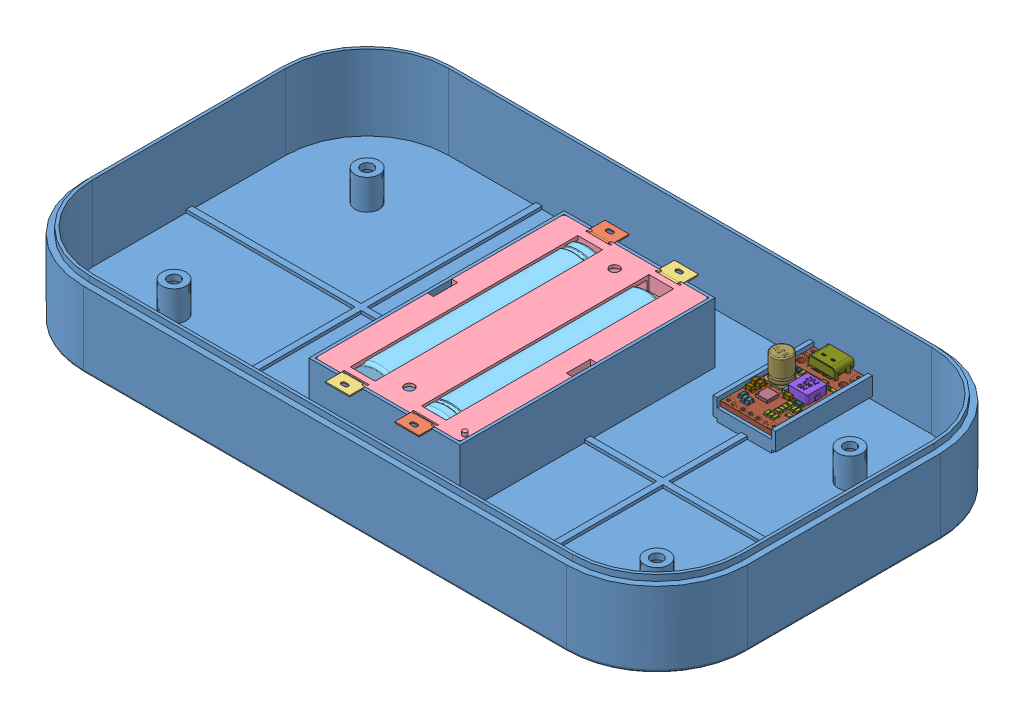
SolidWorks assembly Assem4, configuration Default. Lengths in mm.
Overall size (220 29 124).
46 component instances, 17 part files, 6 mates.
Components (placement in the parent):
- Part Bawah-1: Part Bawah [Default] at (99.8411 94.4112 166.5811) size (220 29 124)
- Hold_21700-2p_smd_bat-1: Hold_21700-2p_smd_bat [Default] at (99.8411 116.4112 166.5811) x (1 0 0) z (0 -1 0) size (48 92.64 22.3)
  - Hold_21700_Con_smd_p-1: Hold_21700_Con_smd_p [Default] at (-11.5 -40 0.8) size (8 9.53 15.7)
  - Hold_21700_Con_smd_m-1: Hold_21700_Con_smd_m [Default] at (-11.5 40 0.8) x (-1 0 0) z (0 0 1) size (8 12.94 15.7)
  - Hold_21700-2p_smd_1-1: Hold_21700-2p_smd_1 [Default] at origin size (48 82.5 17.3)
  - 21700-1: 21700 [Default] at (11.5 36.5 10.5) x (0 0 -1) z (0 1 0) size (21 21 70.2)
  - Hold_21700_Con_smd_p-2: Hold_21700_Con_smd_p [Default] at (11.5 40 0.8) x (-1 0 0) z (0 0 1) size (8 9.53 15.7)
  - Hold_21700_Con_smd_m-2: Hold_21700_Con_smd_m [Default] at (11.5 -40 0.8) size (8 12.94 15.7)
  - 21700-2: 21700 [Default] at (-11.5 -36.5 10.5) x (1 0 0) z (0 -1 0) size (21 21 70.2)
- Penutup baterai-3: Penutup baterai [Default] at (99.8411 95.4112 166.5811) x (1 0 0) z (0 0 -1) size (54 3 94)
- CHARGER BOARD 2S 15W-1: CHARGER BOARD 2S 15W [Default] at (150.6641 102.3529 127.6118) x (0 0 -1) z (1 0 0) size (32.1 10.03 18)
  - 0603-1: 0603 [Default] at (-1.1693 0.1284 6.1184) x (1 0 0) z (0 -1 0) size (2.4 1 0.47)
  - APH0630T-1: APH0630T [Default] at (2.0307 -0.2416 -0.5316) x (0 0 1) z (-1 0 0) size (7 2.9 6.6)
  - Ceramic_Capacitor_0805-1: Ceramic_Capacitor_0805 [Default] at (0.9557 -0.3416 0.8684) x (0 0 1) z (0 1 0) size (3.2 1.65 1.31)
  - LED-1: LED [Default] at (10.5807 -0.3416 -6.4316) x (1 0 0) z (0 1 0) size (1.6 0.8 0.6)
  - LED-2: LED [Default] at (10.5807 -0.3416 -5.1316) x (1 0 0) z (0 1 0) size (1.6 0.8 0.6)
  - PCB BD-1: PCB BD [Default] at (-10.9693 -0.3416 7.9684) size (31 1.64 18)
  - 100uF 35V001-1: 100uF 35V001 [Default] at (5.1507 -0.3416 -5.5516) x (1 0 0) z (0 1 0) size (8.58 8.74 8.41)
  - QFN-16 (4x4x0.9).step-1: QFN-16 (4x4x0.9).step [Default] at (-2.0393 -0.3416 -3.1116) x (1 0 0) z (0 1 0) size (4 4 0.92)
  - Ceramic_Capacitor_0805-2: Ceramic_Capacitor_0805 [Default] at (-2.6443 -0.3416 -8.2316) x (0 0 1) z (0 1 0) size (3.2 1.65 1.31)
  - Ceramic_Capacitor_0805-3: Ceramic_Capacitor_0805 [Default] at (0.0307 -0.3416 -7.3566) x (1 0 0) z (0 1 0) size (3.2 1.65 1.31)
  - Ceramic_Capacitor_0805-4: Ceramic_Capacitor_0805 [Default] at (0.0307 -0.3416 -9.0566) x (1 0 0) z (0 1 0) size (3.2 1.65 1.31)
  - Ceramic_Capacitor_0805-5: Ceramic_Capacitor_0805 [Default] at (10.5557 -0.3416 3.1684) x (0 0 1) z (0 1 0) size (3.2 1.65 1.31)
  - Ceramic_Capacitor_0603-1: Ceramic_Capacitor_0603 [Default] at (2.5307 -0.4668 -1.4816) x (1 0 0) z (0 1 0) size (2.56 1.32 1.05)
  - Ceramic_Capacitor_0603-2: Ceramic_Capacitor_0603 [Default] at (-6.6693 -0.4668 -5.8516) x (1 0 0) z (0 1 0) size (2.56 1.32 1.05)
  - Ceramic_Capacitor_0603-3: Ceramic_Capacitor_0603 [Default] at (-6.6693 -0.4668 -4.4316) x (1 0 0) z (0 1 0) size (2.56 1.32 1.05)
  - 0805-1: 0805 [Default] at (-5.5693 0.1827 -7.5816) x (1 0 0) z (0 -1 0) size (3.04 1.32 0.58)
  - 0805-2: 0805 [Default] at (0.9557 0.1827 4.2684) x (0 0 -1) z (0 -1 0) size (3.04 1.32 0.58)
  - 0603-2: 0603 [Default] at (10.5807 0.1284 -7.5816) x (1 0 0) z (0 -1 0) size (2.4 1 0.47)
  - 0603-3: 0603 [Default] at (10.5807 0.1284 0.8184) x (1 0 0) z (0 -1 0) size (2.4 1 0.47)
  - 0603-4: 0603 [Default] at (10.3807 0.1284 6.2884) x (0 0 -1) z (0 -1 0) size (2.4 1 0.47)
  - 0603-5: 0603 [Default] at (-6.6693 0.1284 4.1684) x (1 0 0) z (0 -1 0) size (2.4 1 0.47)
  - 0603-6: 0603 [Default] at (-2.0193 0.1284 2.8684) x (0 0 -1) z (0 -1 0) size (2.4 1 0.47)
  - 0603-7: 0603 [Default] at (-0.4693 0.1284 2.8684) x (0 0 -1) z (0 -1 0) size (2.4 1 0.47)
  - 0603-8: 0603 [Default] at (-4.0193 0.1284 6.1684) x (0 0 -1) z (0 -1 0) size (2.4 1 0.47)
  - 0603-9: 0603 [Default] at (-1.1693 0.1284 4.9684) x (1 0 0) z (0 -1 0) size (2.4 1 0.47)
  - 0603-10: 0603 [Default] at (-3.2193 0.1284 2.8684) x (0 0 -1) z (0 -1 0) size (2.4 1 0.47)
  - 0603-11: 0603 [Default] at (-4.4193 0.1284 2.8684) x (0 0 -1) z (0 -1 0) size (2.4 1 0.47)
  - 0603-12: 0603 [Default] at (-6.6693 0.1284 2.9184) x (1 0 0) z (0 -1 0) size (2.4 1 0.47)
  - 0603-13: 0603 [Default] at (-6.6693 0.1284 1.6684) x (1 0 0) z (0 -1 0) size (2.4 1 0.47)
  - 0603-14: 0603 [Default] at (10.5807 0.1284 -0.3816) x (1 0 0) z (0 -1 0) size (2.4 1 0.47)
  - 0603-15: 0603 [Default] at (10.5807 0.1284 -1.5816) x (1 0 0) z (0 -1 0) size (2.4 1 0.47)
  - 0603-16: 0603 [Default] at (10.5807 0.1284 -2.7816) x (1 0 0) z (0 -1 0) size (2.4 1 0.47)
  - 0603-17: 0603 [Default] at (10.5807 0.1284 -3.9816) x (1 0 0) z (0 -1 0) size (2.4 1 0.47)
  - USB C-1: USB C [Default] at (19.9307 -1.2316 42.5984) x (0 0 -1) z (0 1 0) size (8.94 7.9 4.2)
  - DIODE-1: DIODE [Default] at (15.2551 -0.6016 53.4886) x (0 0 -1) z (0 1 0)
Mates (geometry in assembly coordinates):
- Coincident1: coincident anti-aligned: plane of Part Bawah-1 through (99.8411 81.8628 207.8311) normal (0 0 -1); plane of Hold_21700-2p_smd_bat-1/Hold_21700-2p_smd_1-1 through (99.8411 116.4112 207.8311) normal (0 0 1)
- Coincident2: coincident aligned: line of Part Bawah-1 through (75.8411 116.4112 125.3311) axis (0 0 1); line of Hold_21700-2p_smd_bat-1/Hold_21700-2p_smd_1-1 through (75.8411 116.4112 126.3311) axis (0 0 1)
- Coincident8: coincident anti-aligned: line of Part Bawah-1 through (72.8411 94.4112 210.5811) axis (1 0 0); line of Penutup baterai-3 through (126.8411 94.4112 210.5811) axis (-1 0 0)
- Coincident9: coincident anti-aligned: line of Part Bawah-1 through (126.8411 94.4112 210.5811) axis (0 0 -1); line of Penutup baterai-3 through (126.8411 94.4112 122.5811) axis (0 0 1)
- Coincident10: coincident anti-aligned: plane of Part Bawah-1 through (99.8411 100.4112 166.5811) normal (0 1 0); plane of CHARGER BOARD 2S 15W-1/PCB BD-1 through (158.6326 100.4112 138.5811) normal (0 -1 0)
- Coincident11: coincident aligned: line of Part Bawah-1 through (158.8411 100.4112 107.5811) axis (-1 0 0); line of CHARGER BOARD 2S 15W-1/PCB BD-1 through (158.6326 100.4112 107.5811) axis (-1 0 0)
